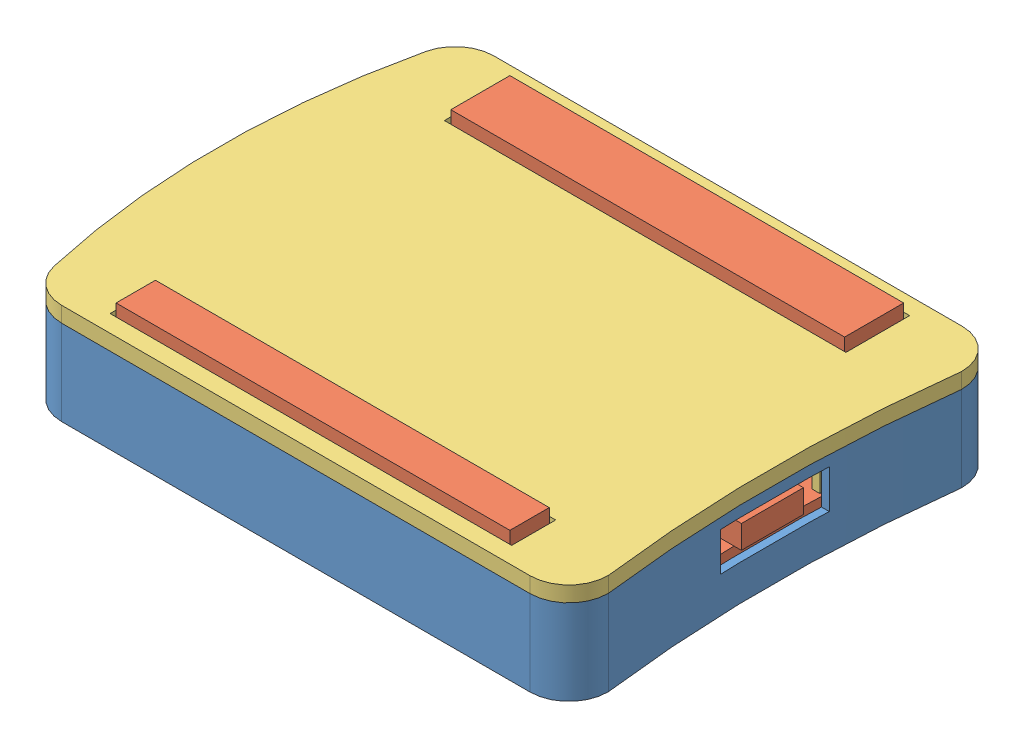
SolidWorks assembly Assem1, configuration Default. Lengths in mm.
Overall size (73.01 14.3 55.74).
3 component instances, 3 part files, 6 mates.
Components (placement in the parent):
- Base-1: Base [Default] at (35.8516 38.679 81.617) size (73.01 11 55.74)
- GreatFet One Board-1: GreatFet One Board [Default] at (35.8516 42.679 81.617) size (71.61 10.3 53.34)
- Lid-1: Lid [Default] at (35.8516 49.679 81.617) size (73.01 7 55.74)
Mates (geometry in assembly coordinates):
- Concentric1: concentric aligned: circle of Base-1; circle of GreatFet One Board-1
- Concentric2: concentric aligned: circle of Base-1; circle of GreatFet One Board-1
- Concentric3: concentric: circle of GreatFet One Board-1; circle of Lid-1
- Concentric4: concentric: circle of GreatFet One Board-1; circle of Lid-1
- Coincident6: coincident anti-aligned: plane of Base-1 through (5.3716 42.679 61.297) normal (0 1 0); plane of GreatFet One Board-1 through (66.3316 42.679 58.757) normal (0 -1 0)
- Coincident7: coincident anti-aligned: plane of Base-1 through (253.1787 49.679 81.617) normal (0 1 0); plane of Lid-1 through (253.1787 49.679 81.617) normal (0 -1 0)
